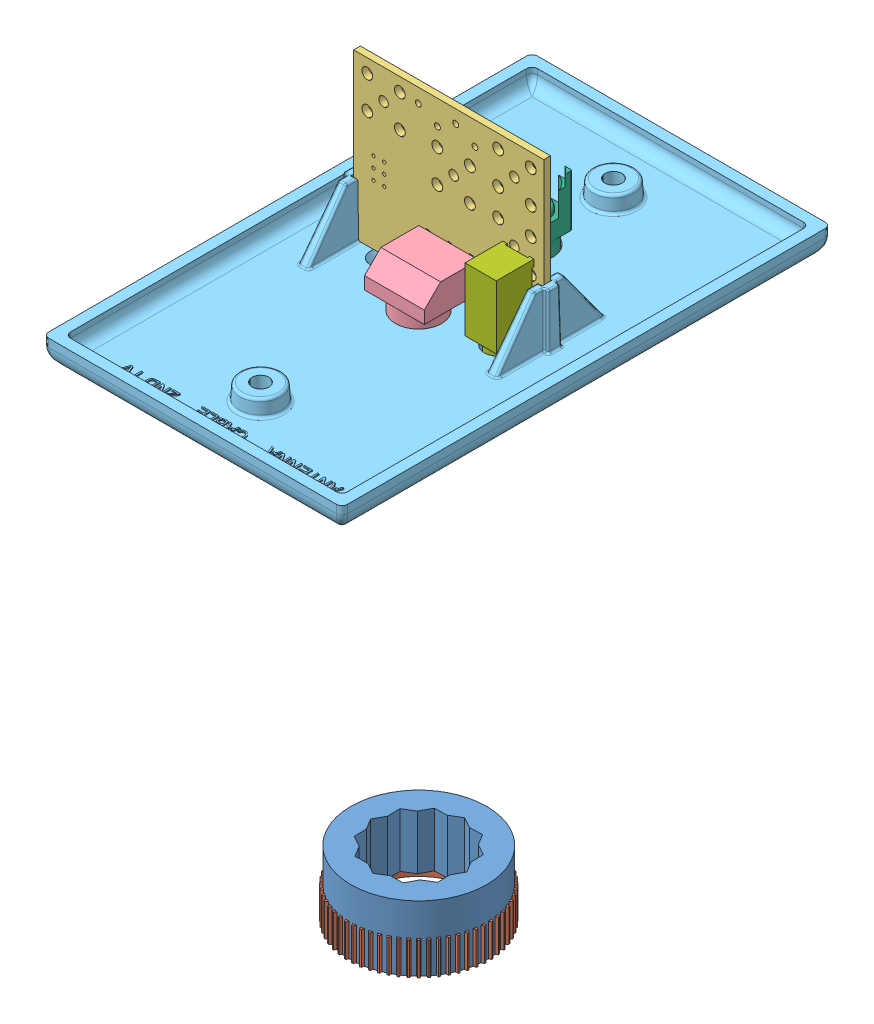
SolidWorks assembly SocketAssembly, configuration Default. Lengths in mm.
Overall size (69.85 161.84 114.3).
8 component instances, 8 part files, 14 mates.
Components (placement in the parent):
- SocketWrench-1: SocketWrench [Default] at origin size (31.75 15.24 31.75)
- spur gear_ai-2: spur gear_ai [Inch - Spur gear 48DP 60T 20PA 0.3FW ---S60N3.0H2.0L1.0N] at (0 -2.54 0) x (0 1 0) z (0 0 1) size (7.62 32.78 32.78)
- Power Supply Board Rev B-1: Power Supply Board Rev B [Default] at (0.0762 140.2453 -6.9342) x (1 0 0) z (0 1 0) size (44.45 1.57 38.1)
- Right Angle Connector-1: Right Angle Connector [Default] at (0.0762 130.3393 -6.9342) x (0 -1 0) z (-1 0 0) size (24.26 17.14 13.97)
- Wall plate 065850 SM LED Rev C-2: Wall plate 065850 SM LED Rev C [Default] at (-0.0508 125.0053 -4.318) x (-1 0 0) z (0 0 1) size (69.85 16.51 114.3)
- 25-7650 Connector-2: 25-7650 Connector [Default] at (-0.0508 124.1593 -26.416) x (1 0 0) z (0 0 -1) size (9.53 25.4 9.53)
- Switch-1: Switch [Default] at (17.6403 129.4368 -6.477) x (-1 0 0) z (0 1 0) size (7.32 10.92 30.28)
- CustomNut-1: CustomNut [Default] at (0.0762 112.2304 0.1143) x (0.132494 0 -0.991184) z (0.991184 0 0.132494) size (12.82 2.57 11.1)
Mates (geometry in assembly coordinates):
- Coincident3: coincident aligned: circle of SocketWrench-1; plane of spur gear_ai-2 through (0 -2.54 0) normal (0 -1 0)
- Concentric6: concentric anti-aligned: circle of Power Supply Board Rev B-1; circle of Right Angle Connector-1
- Concentric7: concentric anti-aligned: circle of Power Supply Board Rev B-1; circle of Right Angle Connector-1
- Coincident22: coincident aligned: line of Power Supply Board Rev B-1 through (22.3012 159.2953 -8.509) axis (0 -1 0); line of Wall plate 065850 SM LED Rev C-2 through (22.3012 133.3873 -8.509) axis (0 -1 0)
- Parallel12: parallel anti-aligned: plane of Power Supply Board Rev B-1 through (-22.1488 121.1953 -8.509) normal (-1 0 0); plane of Wall plate 065850 SM LED Rev C-2 through (-22.4028 133.8953 -97.8236) normal (1 0 0)
- Coincident25: coincident anti-aligned: plane of Power Supply Board Rev B-1 through (-22.1488 121.1953 -8.509) normal (0 -1 0); plane of Wall plate 065850 SM LED Rev C-2 through (-34.9758 121.1953 52.832) normal (0 1 0)
- Coincident26: coincident anti-aligned: plane of Power Supply Board Rev B-1 through (22.3012 159.2953 -6.9342) normal (0 0 1); plane of Right Angle Connector-1 through (7.0612 124.6243 -6.9342) normal (0 0 -1)
- Concentric20: concentric aligned: circle of SocketWrench-1; circle of Wall plate 065850 SM LED Rev C-2
- Concentric22: concentric aligned: circle of Wall plate 065850 SM LED Rev C-2; circle of 25-7650 Connector-2
- Parallel13: parallel anti-aligned: plane of Wall plate 065850 SM LED Rev C-2 through (34.8742 118.6553 -61.468) normal (0 0 -1)
- Concentric23: concentric aligned: circle of Wall plate 065850 SM LED Rev C-2; circle of Switch-1
- Parallel14: parallel anti-aligned: plane of Power Supply Board Rev B-1 through (22.3012 159.2953 -6.9342) normal (0 0 1); plane of Switch-1 through (12.7254 138.022 -6.477) normal (0 0 -1)
- Parallel15: parallel aligned: plane of Power Supply Board Rev B-1 through (22.3012 159.2953 -8.509) normal (0 0 -1); plane of 25-7650 Connector-2 through (-4.8133 136.2243 -31.1785) normal (0 0 -1)
- Concentric24: concentric anti-aligned: circle of Right Angle Connector-1; circle of CustomNut-1
